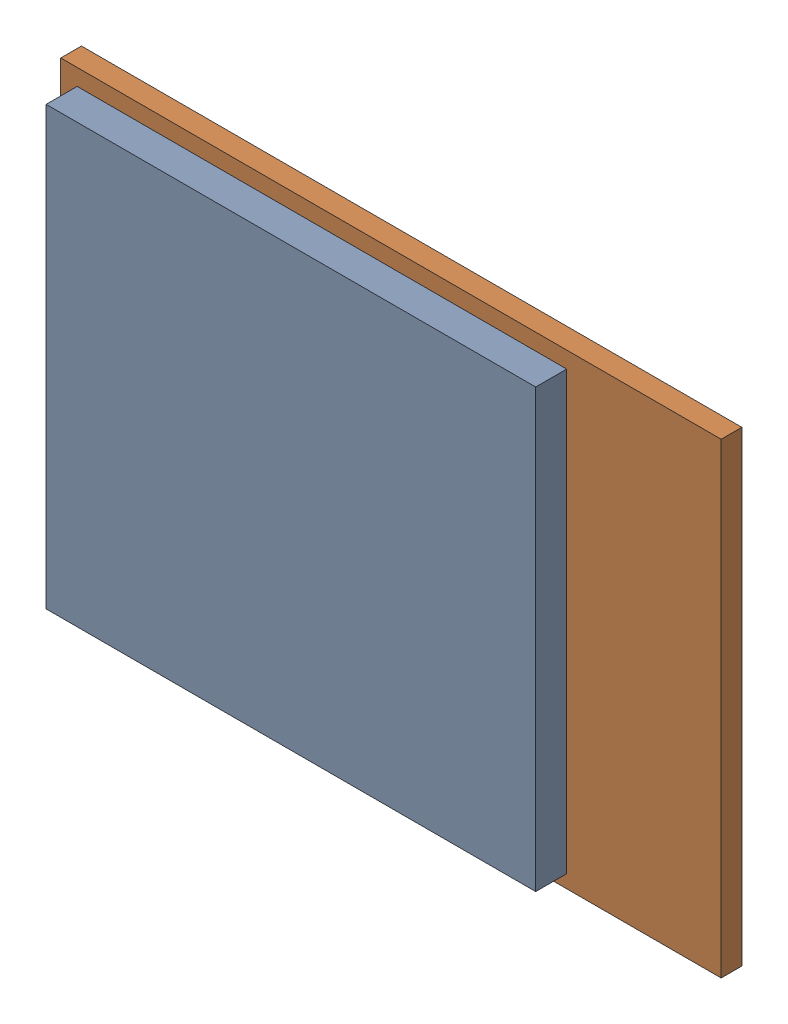
SolidWorks assembly M1, configuration Default. Lengths in mm.
Overall size (25.53 18.03 2).
4 component instances, 2 part files, 0 mates.
Components (placement in the parent):
- 76823120-1: 76823120 [Default] at (34.633 16.3365 0.8) size (18.92 16.89 1.2)
  - Extruded_2-1: Extruded_2 [Default] at origin size (18.92 16.89 1.2)
- 76822984-1: 76822984 [Default] at (37.3 16.4 0) size (25.53 18.03 0.8)
  - Extruded_3-1: Extruded_3 [Default] at origin size (25.53 18.03 0.8)
